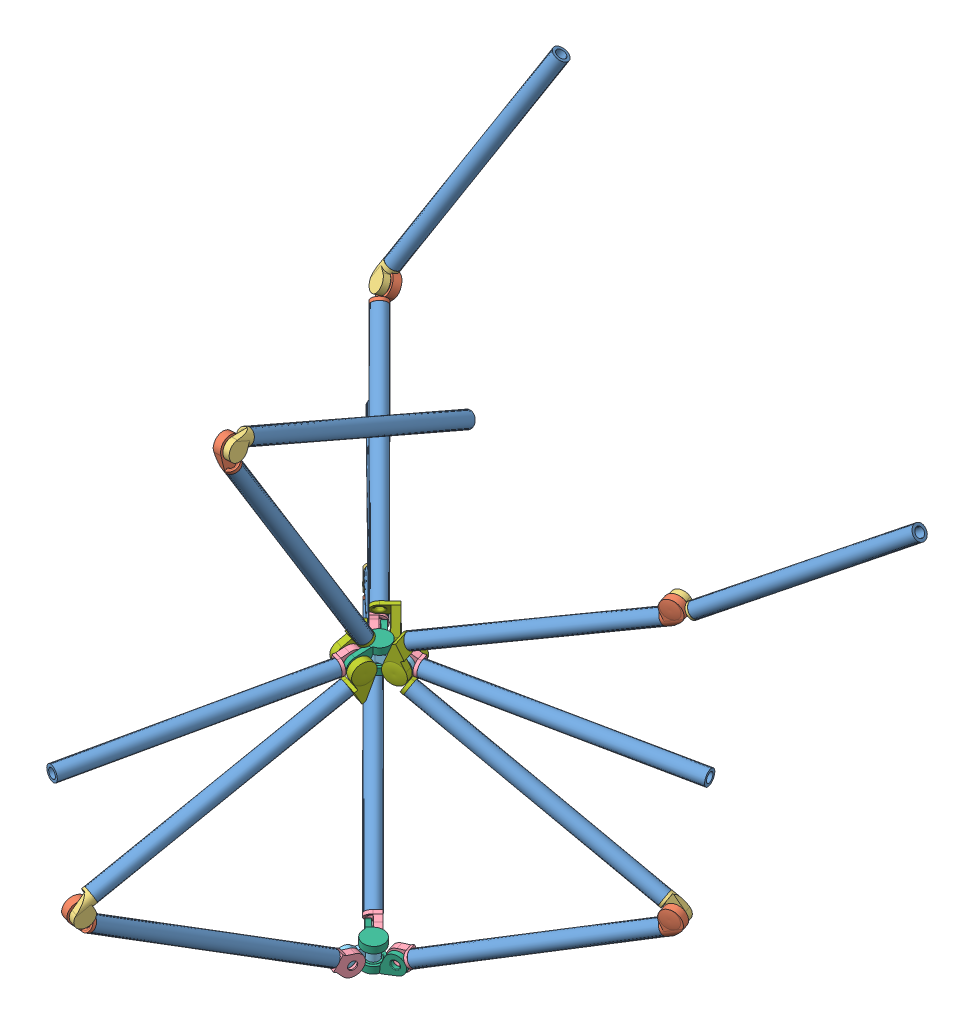
SolidWorks assembly t1d1_part, configuration 默认. Lengths in mm.
Overall size (278.08 283.02 220.4).
56 component instances, 7 part files, 118 mates.
Components (placement in the parent):
- bar-1: bar [默认] at (113.5936 52.6353 -61.7131) x (-0.371564 0.867268 0.331341) z (0.328288 -0.211101 0.920686) size (6.3 100 6.3)
- bar-2: bar [默认] at (-8.2825 55.0819 62.6865) x (0.670703 0.700633 -0.243457) z (-0.719702 0.535343 -0.442082) size (6.3 100 6.3)
- bar-3: bar [默认] at (-59.7571 133.9283 -111.4996) x (-0.460825 0.690997 0.556923) z (0.533513 0.717169 -0.448366) size (6.3 100 6.3)
- bar-4: bar [默认] at (-6.9526 119.8351 80.0325) x (-0.815608 0.545725 -0.192271) z (-0.521971 -0.837348 -0.162465) size (6.3 100 6.3)
- bar-5: bar [默认] at (-46.8523 183.5065 -99.8858) x (-0.20381 0.64879 0.733166) z (0.764001 0.573683 -0.29528) size (6.3 100 6.3)
- bar-6: bar [默认] at (15.7067 217.8918 25.4283) x (0.705225 0.392487 -0.590433) z (-0.706999 0.327058 -0.627044) size (6.3 100 6.3)
- bar-7: bar [默认] at (120.6827 174.6503 -54.6895) x (0.342954 -0.260417 0.902533) z (0.330016 -0.866153 -0.375323) size (6.3 100 6.3)
- bar-8: bar [默认] at (132.1822 116.8072 -62.1166) x (-0.146879 -0.935632 -0.320965) z (-0.23324 0.348095 -0.907981) size (6.3 100 6.3)
- bar-9: bar [默认] at (-53.4278 78.5429 -104.0803) x (-0.389663 -0.567593 0.725259) z (-0.635408 0.735738 0.234405) size (6.3 100 6.3)
- bar-10: bar [默认] at (-7.3739 66.2514 62.9663) x (0.309994 0.781908 0.540855) z (-0.915418 0.399093 -0.052287) size (6.3 100 6.3)
- bar-11: bar [默认] at (114.1097 63.8126 -61.033) x (0.223107 0.716499 -0.660948) z (0.520023 0.486015 0.7024) size (6.3 100 6.3)
- bar-12: bar [默认] at (-54.4851 67.4131 -104.8993) x (-0.705787 0.003815 0.708414) z (0.411489 0.816206 0.405567) size (6.3 100 6.3)
- class2_joint-1: class2_joint [默认] at (100.9145 46.0526 -58.7015) x (0.418964 -0.889781 -0.180995) z (0.265145 -0.070759 0.961609) size (27.33 28 6.67) (flexible)
  - joint_bearing-1: joint_bearing [默认] at origin size (10.85 25 6.67)
  - joint_shaft-1: joint_shaft [默认] at (-22.0945 11.9921 0) x (-0.544886 0.83851 0) z (0 0 -1) size (10.35 24.5 6.35)
- class2_joint-2: class2_joint [默认] at (-5.6632 48.1948 50.0823) x (-0.189599 -0.877668 0.440171) z (-0.965332 0.084713 -0.246895) size (27.33 28 6.67) (flexible)
  - joint_bearing-1: joint_bearing [默认] at origin size (10.85 25 6.67)
  - joint_shaft-1: joint_shaft [默认] at (-22.0945 11.9921 0) x (-0.544886 0.83851 0) z (0 0 -1) size (10.35 24.5 6.35)
- class2_joint-3: class2_joint [默认] at (107.8424 168.4224 -51.6073) x (0.395255 -0.901683 -0.175333) z (0.265145 -0.070759 0.961609) size (27.33 28 6.67) (flexible)
  - joint_bearing-1: joint_bearing [默认] at origin size (10.85 25 6.67)
  - joint_shaft-1: joint_shaft [默认] at (-4.0164 41.2273 0) x (0.981197 0.193011 0) z (0 0 -1) size (10.35 24.5 6.35)
- class2_joint-4: class2_joint [默认] at (16.4805 205.341 18.0095) x (0.032784 -0.507081 0.861275) z (-0.998056 -0.062307 0.001307) size (27.33 28 6.67) (flexible)
  - joint_bearing-1: joint_bearing [默认] at origin size (10.85 25 6.67)
  - joint_shaft-1: joint_shaft [默认] at (-17.9686 5.9577 0) x (-0.801912 0.597442 0) z (0 0 -1) size (10.35 24.5 6.35)
- class2_joint-9: class2_joint [默认] at (-46.0658 58.978 -96.4658) x (-0.420307 -0.816094 -0.396652) z (0.700571 -0.01405 -0.713444) size (27.33 28 6.67) (flexible)
  - joint_bearing-1: joint_bearing [默认] at origin size (10.85 25 6.67)
  - joint_shaft-1: joint_shaft [默认] at (-22.0945 11.9921 0) x (-0.544886 0.83851 0) z (0 0 -1) size (10.35 24.5 6.35)
- joint_bearing_central-1: joint_bearing_central [默认] at (7.0386 14.7969 -11.0395) x (-0.191063 -0.877539 0.439796) z (0.965044 -0.086044 0.247563) size (9 25 6.17)
- mid_ear-1: mid_ear [默认] at (12.7874 2.9254 -37.5756) x (0.965044 -0.086044 0.247563) z (-0.251035 -0.032026 0.967448) size (5 8 15.5)
- side_ear-1: side_ear [默认] at (13.164 7.9042 -37.313) x (0.699933 -0.015288 -0.714045) z (-0.710226 0.090529 -0.698128) size (9 9.5 17.5)
- side_ear-2: side_ear [默认] at (12.7874 2.9254 -37.5756) x (-0.265145 0.070759 -0.961609) z (0.961262 -0.058502 -0.269355) size (9 9.5 17.5)
- joint_bearing_central-2: joint_bearing_central [默认] at (-5.238 18.0734 -55.569) x (0.421369 0.816072 0.395569) z (0.699933 -0.015288 -0.714045) size (9 25 6.17)
- joint_bearing_central-3: joint_bearing_central [默认] at (39.4298 14.1311 -44.0971) x (0.418964 -0.889781 -0.180995) z (-0.265145 0.070759 -0.961609) size (9 25 6.17)
- joint_bearing_central-4: joint_bearing_central [默认] at (50.0904 121.8032 -39.1137) x (-0.075315 -0.995776 -0.052506) z (-0.265145 0.070759 -0.961609) size (9 25 6.17)
- mid_ear-2: mid_ear [默认] at (21.5449 121.0396 -31.299) x (-0.265145 0.070759 -0.961609) z (0.961262 -0.058502 -0.269355) size (5 8 15.5)
- side_ear-3: side_ear [默认] at (21.9214 126.0184 -31.0364) x (-0.965401 0.085998 -0.246183) z (-0.249659 -0.032148 0.9678) size (9 9.5 17.5)
- side_ear-4: side_ear [默认] at (21.5449 121.0396 -31.299) x (-0.700945 0.015417 0.713048) z (-0.709227 0.090507 -0.699146) size (9 9.5 17.5)
- joint_bearing_central-5: joint_bearing_central [默认] at (14.3682 122.5806 -2.6176) x (0.075315 0.995776 0.052506) z (-0.965401 0.085998 -0.246183) size (9 25 6.17)
- joint_bearing_central-6: joint_bearing_central [默认] at (0.8109 126.199 -51.7925) x (-0.075315 -0.995776 -0.052506) z (-0.700945 0.015417 0.713048) size (9 25 6.17)
- joint_bearing_c9-1: joint_bearing_c9 [默认] at (5.4279 140.81 -47.5699) x (0.36594 0.865912 0.341006) z (0.700945 -0.015417 -0.713048) size (14.86 25 10.02)
- joint_bearing_c9-2: joint_bearing_c9 [默认] at (20.233 144.4782 -17.9667) x (0.255329 0.503604 -0.825342) z (-0.965401 0.085998 -0.246183) size (14.86 25 10.02)
- joint_bearing_c9-3: joint_bearing_c9 [默认] at (43.6975 106.5484 -38.4735) x (-0.499899 -0.862887 0.074343) z (-0.265145 0.070759 -0.961609) size (14.86 25 10.02)
- joint_bearing_c9-4: joint_bearing_c9 [默认] at (45.5758 138.2212 -36.6608) x (-0.395255 0.901683 0.175333) z (0.265145 -0.070759 0.961609) size (14.86 25 10.02)
- joint_bearing_c9-5: joint_bearing_c9 [默认] at (14.5513 107.1494 -8.726) x (0.045702 -0.873647 -0.484409) z (0.965401 -0.085998 0.246183) size (14.86 25 10.02)
- joint_bearing_c9-6: joint_bearing_c9 [默认] at (3.5039 110.0979 -48.7972) x (0.253489 -0.929104 0.269275) z (-0.700945 0.015417 0.713048) size (14.86 25 10.02)
- class2_joint-10: class2_joint [默认] at (-37.9145 176.2071 -90.9418) x (-0.678772 -0.729666 0.082807) z (0.405592 -0.466507 -0.786045) size (27.33 28 6.67) (flexible)
  - joint_bearing-1: joint_bearing [默认] at origin size (10.85 25 6.67)
  - joint_shaft-1: joint_shaft [默认] at (-21.476 30.2674 0) x (0.330272 0.943886 0) z (0 0 -1) size (10.35 24.5 6.35)
- bar-13: bar [默认] at (-4.4185 279.9281 -135.2153) x (-0.501301 -0.026657 -0.864862) z (-0.745934 0.519847 0.416343) size (6.3 100 6.3)
- bar-14: bar [默认] at (209.6928 240.2368 -74.4062) x (0.27836 -0.089864 0.956264) z (0.551093 -0.800481 -0.235642) size (6.3 100 6.3)
- bar-15: bar [默认] at (17.5327 186.5748 -73.1816) x (-0.999563 0.00835 -0.028341) z (0.01865 0.92229 -0.386047) size (6.3 100 6.3)
- mid_ear-3: mid_ear [默认] at (21.5449 121.0396 -31.299) x (-0.265145 0.070759 -0.961609) z (0.961262 -0.058502 -0.269355) size (5 8 15.5)
- joint_bearing_central-7: joint_bearing_central [默认] at (50.0904 121.8032 -39.1137) x (-0.075315 -0.995776 -0.052506) z (-0.265145 0.070759 -0.961609) size (9 25 6.17)
- side_ear-5: side_ear [默认] at (12.7874 2.9254 -37.5756) x (-0.265145 0.070759 -0.961609) z (0.961262 -0.058502 -0.269355) size (9 9.5 17.5)
- side_ear-6: side_ear [默认] at (13.164 7.9042 -37.313) x (0.699933 -0.015288 -0.714045) z (-0.710226 0.090529 -0.698128) size (9 9.5 17.5)
- mid_ear-4: mid_ear [默认] at (12.7874 2.9254 -37.5756) x (0.965044 -0.086044 0.247563) z (-0.251035 -0.032026 0.967448) size (5 8 15.5)
Mates (geometry in assembly coordinates):
- 同心4: concentric anti-aligned: cylinder of bar-1 through (26.7508 7.5484 -41.0855) axis (0.868428 0.450869 -0.206276) radius 2; cylinder of class2_joint-1/joint_bearing-1 through (114.8094 53.2665 -62.0019) axis (-0.868428 -0.450869 0.206276) radius 2
- 重合4: coincident anti-aligned: plane of bar-1 through (113.5936 52.6353 -61.7131) normal (0.868428 0.450869 -0.206276); plane of class2_joint-1/joint_bearing-1 through (113.5936 52.6353 -61.7131) normal (-0.868428 -0.450869 0.206276)
- 同心5: concentric anti-aligned: cylinder of bar-11 through (31.6598 113.8545 -34.6167) axis (0.824499 -0.500419 -0.264163) radius 2; cylinder of class2_joint-1/joint_shaft-1 through (115.264 63.112 -61.4028) axis (-0.824499 0.500419 0.264163) radius 2
- 重合6: coincident anti-aligned: plane of bar-11 through (114.1097 63.8126 -61.033) normal (0.824499 -0.500419 -0.264163); plane of class2_joint-1/joint_shaft-1 through (114.1097 63.8126 -61.033) normal (-0.824499 0.500419 0.264163)
- 同心6: concentric anti-aligned: cylinder of bar-2 through (9.6579 7.9097 -23.6438) axis (-0.179404 0.471722 0.863303) radius 2; cylinder of class2_joint-2/joint_bearing-1 through (-8.5337 55.7423 63.8952) axis (0.179404 -0.471722 -0.863303) radius 2
- 重合7: coincident anti-aligned: plane of bar-2 through (-8.2825 55.0819 62.6865) normal (-0.179404 0.471722 0.863303); plane of class2_joint-2/joint_bearing-1 through (-8.2825 55.0819 62.6865) normal (0.179404 -0.471722 -0.863303)
- 同心7: concentric anti-aligned: cylinder of bar-10 through (18.2996 114.1414 -20.9826) axis (-0.256736 -0.478899 0.839489) radius 2; cylinder of class2_joint-2/joint_shaft-1 through (-7.7334 65.581 64.1416) axis (0.256736 0.478899 -0.839489) radius 2
- 重合9: coincident anti-aligned: plane of bar-10 through (-7.3739 66.2514 62.9663) normal (-0.256736 -0.478899 0.839489); plane of class2_joint-2/joint_shaft-1 through (-7.3739 66.2514 62.9663) normal (0.256736 0.478899 -0.839489)
- 同心8: concentric anti-aligned: cylinder of bar-12 through (3.1813 9.6383 -47.1355) axis (-0.576664 0.577748 -0.577638) radius 2; cylinder of class2_joint-9/joint_bearing-1 through (-55.2925 68.2219 -105.708) axis (0.576664 -0.577748 0.577638) radius 2
- 重合10: coincident anti-aligned: plane of bar-12 through (-54.4851 67.4131 -104.8993) normal (-0.576664 0.577748 -0.577638); plane of class2_joint-9/joint_bearing-1 through (-54.4851 67.4131 -104.8993) normal (0.576664 -0.577748 0.577638)
- 同心9: concentric anti-aligned: cylinder of bar-9 through (13.2369 115.4926 -39.346) axis (-0.666648 -0.369497 -0.647343) radius 2; cylinder of class2_joint-9/joint_shaft-1 through (-54.3612 78.0256 -104.9865) axis (0.666648 0.369497 0.647343) radius 2
- 重合12: coincident anti-aligned: plane of bar-9 through (-53.4278 78.5429 -104.0803) normal (-0.666648 -0.369497 -0.647343); plane of class2_joint-9/joint_shaft-1 through (-53.4278 78.5429 -104.0803) normal (0.666648 0.369497 0.647343)
- 同心25: concentric anti-aligned: cylinder of bar-7 through (32.7355 131.9933 -33.5786) axis (0.879472 0.426569 -0.211109) radius 2; cylinder of class2_joint-3/joint_bearing-1 through (121.914 175.2475 -54.985) axis (-0.879472 -0.426569 0.211109) radius 2
- 重合27: coincident anti-aligned: plane of bar-7 through (120.6827 174.6503 -54.6895) normal (0.879472 0.426569 -0.211109); plane of class2_joint-3/joint_bearing-1 through (120.6827 174.6503 -54.6895) normal (-0.879472 -0.426569 0.211109)
- 同心26: concentric anti-aligned: cylinder of bar-6 through (21.0068 131.9274 -25.3855) axis (-0.053001 0.859644 0.508138) radius 2; cylinder of class2_joint-4/joint_bearing-1 through (15.6325 219.0953 26.1397) axis (0.053001 -0.859644 -0.508138) radius 2
- 重合32: coincident anti-aligned: plane of bar-6 through (15.7067 217.8918 25.4283) normal (-0.053001 0.859644 0.508138); plane of class2_joint-4/joint_bearing-1 through (15.7067 217.8918 25.4283) normal (0.053001 -0.859644 -0.508138)
- 同心27: concentric anti-aligned: cylinder of bar-5 through (14.3657 133.5106 -38.6259) axis (-0.61218 0.499959 -0.612598) radius 2; cylinder of class2_joint-10/joint_bearing-1 through (-47.7093 184.2064 -100.7434) axis (0.61218 -0.499959 0.612598) radius 2
- 重合35: coincident anti-aligned: plane of bar-5 through (-46.8523 183.5065 -99.8858) normal (-0.61218 0.499959 -0.612598); plane of class2_joint-10/joint_bearing-1 through (-46.8523 183.5065 -99.8858) normal (0.61218 -0.499959 0.612598)
- 同心28: concentric aligned: cylinder of class2_joint-10/joint_shaft-1 through (-48.8822 193.3484 -106.7742) axis (0.438497 0.853843 -0.280484) radius 2; cylinder of bar-13 through (-48.2683 194.5438 -107.1669) axis (0.438497 0.853843 -0.280484) radius 2
- 重合37: coincident anti-aligned: plane of class2_joint-10/joint_shaft-1 through (-48.2683 194.5438 -107.1669) normal (0.438497 0.853843 -0.280484); plane of bar-13 through (-48.2683 194.5438 -107.1669) normal (-0.438497 -0.853843 0.280484)
- 同心29: concentric aligned: cylinder of class2_joint-3/joint_shaft-1 through (129.9268 180.1489 -56.8338) axis (0.786646 0.592583 -0.173298) radius 2; cylinder of bar-14 through (131.0281 180.9785 -57.0764) axis (0.786646 0.592583 -0.173298) radius 2
- 重合38: coincident anti-aligned: plane of class2_joint-3/joint_shaft-1 through (131.0281 180.9785 -57.0764) normal (0.786646 0.592583 -0.173298); plane of bar-14 through (131.0281 180.9785 -57.0764) normal (-0.786646 -0.592583 0.173298)
- 同心32: concentric aligned: cylinder of class2_joint-4/joint_shaft-1 through (15.209 225.7566 20.3136) axis (0.022915 -0.386407 -0.922044) radius 2; cylinder of bar-15 through (15.2411 225.2156 19.0227) axis (0.022915 -0.386407 -0.922044) radius 2
- 重合39: coincident anti-aligned: plane of class2_joint-4/joint_shaft-1 through (15.2411 225.2156 19.0227) normal (0.022915 -0.386407 -0.922044); plane of bar-15 through (15.2411 225.2156 19.0227) normal (-0.022915 0.386407 0.922044)
- 同心34: concentric anti-aligned: cylinder of bar-2 through (9.6579 7.9097 -23.6438) axis (-0.179404 0.471722 0.863303) radius 2; cylinder of class2_joint-2/joint_bearing-1 through (-8.5337 55.7423 63.8952) axis (0.179404 -0.471722 -0.863303) radius 2
- 同心36: concentric anti-aligned: cylinder of bar-1 through (26.7508 7.5484 -41.0855) axis (0.868428 0.450869 -0.206276) radius 3.15; cylinder of class2_joint-1/joint_bearing-1 through (114.8094 53.2665 -62.0019) axis (-0.868428 -0.450869 0.206276) radius 2
- 重合44: coincident anti-aligned: plane of bar-1 through (113.5936 52.6353 -61.7131) normal (0.868428 0.450869 -0.206276); plane of class2_joint-1/joint_bearing-1 through (113.5936 52.6353 -61.7131) normal (-0.868428 -0.450869 0.206276)
- 同心3: concentric anti-aligned: cylinder of joint_bearing_central-1 through (13.129 4.9115 -28.1184) axis (-0.965044 0.086044 -0.247563) radius 3.15; cylinder of mid_ear-1 through (8.3028 5.3418 -29.3564) axis (0.965044 -0.086044 0.247563) radius 1.65
- 距离4: distance = 0.5 mm anti-aligned: plane of joint_bearing_central-1 through (10.7164 5.1266 -28.7373) normal (-0.965044 0.086044 -0.247563); plane of mid_ear-1 through (13.2719 7.5295 -39.8836) normal (0.965044 -0.086044 0.247563)
- 角度8: planar angle = 2.094395 rad: plane of joint_bearing_central-1 through (0.6375 10.4133 -26.1812) normal (-0.221682 0.235914 0.946151); plane of side_ear-1 through (13.3899 10.8916 -37.1555) normal (0.075315 0.995776 0.052506)
- 同心1: concentric aligned: cylinder of mid_ear-1 through (13.164 7.9042 -37.313) axis (-0.075315 -0.995776 -0.052506) radius 1.65; cylinder of side_ear-1 through (13.3146 9.8958 -37.208) axis (-0.075315 -0.995776 -0.052506) radius 3.15
- 重合2: coincident anti-aligned: plane of mid_ear-1 through (13.164 7.9042 -37.313) normal (0.075315 0.995776 0.052506); plane of side_ear-1 through (13.164 7.9042 -37.313) normal (-0.075315 -0.995776 -0.052506)
- 同心2: concentric anti-aligned: cylinder of mid_ear-1 through (13.164 7.9042 -37.313) axis (-0.075315 -0.995776 -0.052506) radius 1.65; cylinder of side_ear-2 through (12.6368 0.9338 -37.6806) axis (0.075315 0.995776 0.052506) radius 3.15
- 重合3: coincident anti-aligned: plane of mid_ear-1 through (12.7874 2.9254 -37.5756) normal (-0.075315 -0.995776 -0.052506); plane of side_ear-2 through (12.7874 2.9254 -37.5756) normal (0.075315 0.995776 0.052506)
- 角度4: planar angle = 2.094395 rad: plane of side_ear-2 through (5.3043 6.2724 -42.704) normal (0.325091 0.025259 -0.945345); plane of mid_ear-1 through (11.3418 7.7016 -40.3787) normal (-0.965044 0.086044 -0.247563)
- 角度5: planar angle = 2.094395 rad: plane of mid_ear-1 through (11.3418 7.7016 -40.3787) normal (-0.965044 0.086044 -0.247563); plane of joint_bearing_central-2
- 同心42: concentric anti-aligned: cylinder of side_ear-1 through (4.8338 6.2678 -41.9423) axis (0.699933 -0.015288 -0.714045) radius 1.65; cylinder of joint_bearing_central-2 through (8.3335 6.1913 -45.5126) axis (-0.699933 0.015288 0.714045) radius 3.15
- 同心43: concentric anti-aligned: cylinder of side_ear-1 through (4.8338 6.2678 -41.9423) axis (0.699933 -0.015288 -0.714045) radius 1.65; cylinder of joint_bearing_central-2 through (8.3335 6.1913 -45.5126) axis (-0.699933 0.015288 0.714045) radius 3.15
- 距离2: distance = 0.5 mm anti-aligned: plane of side_ear-1 through (12.814 7.9119 -36.956) normal (0.699933 -0.015288 -0.714045); plane of joint_bearing_central-2 through (6.5836 6.2296 -43.7275) normal (-0.699933 0.015288 0.714045)
- 角度6: planar angle = 1.047198 rad: plane of side_ear-1 through (13.3899 10.8916 -37.1555) normal (0.075315 0.995776 0.052506); plane of joint_bearing_central-3 through (6.3421 13.0272 -49.6228) normal (-0.604042 0.774697 -0.187022)
- 角度7: planar angle = 2.094395 rad: plane of joint_bearing_central-2 through (17.6179 2.6651 -19.9624) normal (-0.251263 0.239739 0.937759); plane of side_ear-1 through (13.3899 10.8916 -37.1555) normal (0.075315 0.995776 0.052506)
- 同心44: concentric anti-aligned: cylinder of side_ear-2 through (22.2899 4.7114 -37.4645) axis (-0.265145 0.070759 -0.961609) radius 1.65; cylinder of joint_bearing_central-3 through (20.9642 5.0652 -42.2725) axis (0.265145 -0.070759 0.961609) radius 3.15
- 距离3: distance = 0.5 mm anti-aligned: plane of side_ear-2 through (12.92 2.89 -37.0948) normal (-0.265145 0.070759 -0.961609); plane of joint_bearing_central-3 through (21.627 4.8883 -39.8685) normal (0.265145 -0.070759 0.961609)
- 同心45: concentric aligned: cylinder of bar-2 through (9.6579 7.9097 -23.6438) axis (-0.179404 0.471722 0.863303) radius 2; cylinder of joint_bearing_central-1 through (9.909 7.2493 -24.8524) axis (-0.179404 0.471722 0.863303) radius 2
- 重合47: coincident anti-aligned: plane of bar-2 through (9.6579 7.9097 -23.6438) normal (0.179404 -0.471722 -0.863303); plane of joint_bearing_central-1 through (1.0496 11.5175 -27.404) normal (-0.179404 0.471722 0.863303)
- 平行27: parallel: plane of class2_joint-2/joint_bearing-1; plane of joint_bearing_central-1 through (10.7164 5.1266 -28.7373) normal (-0.965044 0.086044 -0.247563)
- 平行30: parallel: plane of assembly through (0 0 0) normal (0 1 0); plane of side_ear-1 through (13.3899 10.8916 -37.1555) normal (0.075315 0.995776 0.052506); plane of assembly
- 同心46: concentric aligned: cylinder of bar-12 through (3.1813 9.6383 -47.1355) axis (-0.576664 0.577748 -0.577638) radius 2; cylinder of joint_bearing_central-2 through (3.9886 8.8294 -46.3268) axis (-0.576664 0.577748 -0.577638) radius 2
- 重合48: coincident anti-aligned: plane of bar-12 through (3.1813 9.6383 -47.1355) normal (0.576664 -0.577748 0.577638); plane of joint_bearing_central-2 through (-4.84 7.1932 -41.5733) normal (-0.576664 0.577748 -0.577638)
- 平行32: parallel: plane of class2_joint-9/joint_bearing-1; plane of joint_bearing_central-2
- 同心47: concentric aligned: cylinder of bar-1 through (26.7508 7.5484 -41.0855) axis (0.868428 0.450869 -0.206276) radius 2; cylinder of joint_bearing_central-3 through (25.535 6.9172 -40.7967) axis (0.868428 0.450869 -0.206276) radius 2
- 重合49: coincident anti-aligned: plane of bar-1 through (26.7508 7.5484 -41.0855) normal (-0.868428 -0.450869 0.206276); plane of joint_bearing_central-3 through (27.9523 9.6978 -31.3288) normal (0.868428 0.450869 -0.206276)
- 平行33: parallel anti-aligned: plane of class2_joint-1/joint_bearing-1 through (117.3871 58.1205 -62.3555) normal (-0.265145 0.070759 -0.961609); plane of joint_bearing_central-3 through (21.627 4.8883 -39.8685) normal (0.265145 -0.070759 0.961609)
- 同心48: concentric anti-aligned: cylinder of joint_bearing_central-4 through (29.7216 123.1794 -35.9959) axis (0.265145 -0.070759 0.961609) radius 3.15; cylinder of mid_ear-2 through (31.0476 122.8255 -31.1869) axis (-0.265145 0.070759 -0.961609) radius 1.65
- 距离5: distance = 0.5 mm anti-aligned: plane of joint_bearing_central-4 through (30.3845 123.0025 -33.5919) normal (0.265145 -0.070759 0.961609); plane of mid_ear-2 through (19.6113 125.6315 -29.908) normal (-0.265145 0.070759 -0.961609)
- 同心12: concentric aligned: cylinder of joint_bearing_central-4 through (29.5424 123.2272 -36.646) axis (0.265145 -0.070759 0.961609) radius 1.8; cylinder of joint_bearing_c9-3 through (28.7207 123.4465 -39.626) axis (0.265145 -0.070759 0.961609) radius 3.15
- 距离11: distance = 0.5 mm anti-aligned: plane of joint_bearing_c9-3 through (29.4565 123.2501 -36.9575) normal (0.265145 -0.070759 0.961609); plane of joint_bearing_central-4 through (29.5891 123.2148 -36.4767) normal (-0.265145 0.070759 -0.961609)
- 角度1: planar angle = 2.094395 rad: plane of joint_bearing_central-4 through (11.0012 73.6035 -33.1279) normal (-0.325091 -0.025259 0.945345); plane of joint_bearing_central-5 through (15.1528 72.8717 -25.2045) normal (-0.959979 0.086651 -0.26633)
- 平行5: parallel: plane of joint_bearing_central-4; plane of side_ear-3 through (22.3132 128.8711 -30.9346) normal (0.075315 0.995776 0.052506)
- 同心49: concentric aligned: cylinder of mid_ear-2 through (21.9214 126.0184 -31.0364) axis (-0.075315 -0.995776 -0.052506) radius 1.65; cylinder of side_ear-3 through (22.0721 128.01 -30.9314) axis (-0.075315 -0.995776 -0.052506) radius 3.15
- 重合50: coincident anti-aligned: plane of mid_ear-2 through (21.9214 126.0184 -31.0364) normal (0.075315 0.995776 0.052506); plane of side_ear-3 through (21.9214 126.0184 -31.0364) normal (-0.075315 -0.995776 -0.052506)
- 同心50: concentric anti-aligned: cylinder of mid_ear-2 through (21.9214 126.0184 -31.0364) axis (-0.075315 -0.995776 -0.052506) radius 1.65; cylinder of side_ear-4 through (21.3942 119.048 -31.404) axis (0.075315 0.995776 0.052506) radius 3.15
- 重合51: coincident anti-aligned: plane of mid_ear-2 through (21.5449 121.0396 -31.299) normal (-0.075315 -0.995776 -0.052506); plane of side_ear-4 through (21.5449 121.0396 -31.299) normal (0.075315 0.995776 0.052506)
- 同心11: concentric aligned: cylinder of mid_ear-2 through (31.0476 122.8255 -31.1869) axis (-0.265145 0.070759 -0.961609) radius 1.65; cylinder of joint_bearing_c9-4 through (32.0483 122.5585 -27.5578) axis (-0.265145 0.070759 -0.961609) radius 3.15
- 距离10: distance = 1 mm anti-aligned: plane of mid_ear-2 through (20.1416 125.49 -27.9848) normal (0.265145 -0.070759 0.961609); plane of joint_bearing_c9-4 through (31.3125 122.7548 -30.2263) normal (-0.265145 0.070759 -0.961609)
- 角度2: planar angle = 2.094395 rad: plane of joint_bearing_central-6; plane of mid_ear-2
- 同心51: concentric anti-aligned: cylinder of side_ear-3 through (21.8997 123.0247 -21.8421) axis (-0.965401 0.085998 -0.246183) radius 1.65; cylinder of joint_bearing_central-5 through (17.0727 123.4547 -23.073) axis (0.965401 -0.085998 0.246183) radius 3.15
- 同心52: concentric anti-aligned: cylinder of side_ear-3 through (21.8997 123.0247 -21.8421) axis (-0.965401 0.085998 -0.246183) radius 1.65; cylinder of joint_bearing_central-5 through (17.0727 123.4547 -23.073) axis (0.965401 -0.085998 0.246183) radius 3.15
- 距离12: distance = 0.5 mm anti-aligned: plane of side_ear-3 through (22.4041 125.9754 -30.9134) normal (-0.965401 0.085998 -0.246183); plane of joint_bearing_central-5 through (19.4862 123.2397 -22.4575) normal (0.965401 -0.085998 0.246183)
- 同心53: concentric aligned: cylinder of side_ear-3 through (21.8997 123.0247 -21.8421) axis (-0.965401 0.085998 -0.246183) radius 1.65; cylinder of joint_bearing_c9-5 through (25.5441 122.7 -20.9127) axis (-0.965401 0.085998 -0.246183) radius 3.15
- 距离7: distance = 1 mm anti-aligned: plane of side_ear-3 through (21.8997 123.0247 -21.8421) normal (0.965401 -0.085998 0.246183); plane of joint_bearing_c9-5 through (22.8651 122.9387 -21.5959) normal (-0.965401 0.085998 -0.246183)
- 平行3: parallel: plane of side_ear-3 through (22.3132 128.8711 -30.9346) normal (0.075315 0.995776 0.052506); plane of joint_bearing_central-6 through (19.2333 127.6321 -47.2995) normal (0.075315 0.995776 0.052506)
- 平行4: parallel: plane of side_ear-3 through (22.3132 128.8711 -30.9346) normal (0.075315 0.995776 0.052506); plane of joint_bearing_central-5 through (27.6126 125.2571 -14.2778) normal (0.075315 0.995776 0.052506)
- 相切1: tangent: cylinder of side_ear-3 through (22.3132 128.8711 -30.9346) axis (-0.075315 -0.995776 -0.052506) radius 4.5; plane of joint_bearing_c9-4
- 相切2: tangent: cylinder of side_ear-3 through (22.3132 128.8711 -30.9346) axis (-0.075315 -0.995776 -0.052506) radius 4.5; plane of joint_bearing_c9-1
- 相切3: tangent: cylinder of side_ear-3 through (22.3132 128.8711 -30.9346) axis (-0.075315 -0.995776 -0.052506) radius 4.5; plane of joint_bearing_c9-2
- 同心54: concentric anti-aligned: cylinder of side_ear-4 through (17.1025 124.305 -39.2426) axis (-0.700945 0.015417 0.713048) radius 1.65; cylinder of joint_bearing_central-6 through (13.5977 124.3821 -35.6774) axis (0.700945 -0.015417 -0.713048) radius 3.15
- 距离13: distance = 0.5 mm anti-aligned: plane of side_ear-4 through (21.8953 121.0319 -31.6555) normal (-0.700945 0.015417 0.713048); plane of joint_bearing_central-6 through (15.3501 124.3436 -37.46) normal (0.700945 -0.015417 -0.713048)
- 同心55: concentric aligned: cylinder of side_ear-4 through (17.1025 124.305 -39.2426) axis (-0.700945 0.015417 0.713048) radius 1.65; cylinder of joint_bearing_c9-1 through (19.7485 124.2468 -41.9344) axis (-0.700945 0.015417 0.713048) radius 3.15
- 距离14: distance = 1 mm anti-aligned: plane of side_ear-4 through (17.1025 124.305 -39.2426) normal (0.700945 -0.015417 -0.713048); plane of joint_bearing_c9-1 through (17.8034 124.2896 -39.9557) normal (-0.700945 0.015417 0.713048)
- 相切7: tangent: cylinder of side_ear-4 through (21.4848 117.9176 -31.5121) axis (0.075315 0.995776 0.052506) radius 4.5; plane of joint_bearing_c9-6 through (10.5716 113.0253 -33.0017) normal (0.640668 -0.428445 0.637164)
- 相切8: tangent: cylinder of side_ear-4 through (21.4848 117.9176 -31.5121) axis (0.075315 0.995776 0.052506) radius 4.5; plane of joint_bearing_c9-3 through (27.4149 112.1343 -40.3321) normal (-0.926701 -0.294179 0.233847)
- 相切9: tangent: cylinder of side_ear-4 through (21.3189 118.0522 -31.4565) axis (0.075315 0.995776 0.052506) radius 4.5; plane of joint_bearing_c9-5 through (25.0793 111.479 -22.0957) normal (0.208581 -0.311955 -0.926919)
- 同心10: concentric aligned: cylinder of joint_bearing_central-5 through (16.4201 123.5128 -23.2394) axis (0.965401 -0.085998 0.246183) radius 1.8; cylinder of joint_bearing_c9-2 through (13.4283 123.7793 -24.0023) axis (0.965401 -0.085998 0.246183) radius 3.15
- 距离9: distance = 0.5 mm anti-aligned: plane of joint_bearing_c9-2 through (16.1073 123.5407 -23.3192) normal (0.965401 -0.085998 0.246183); plane of joint_bearing_central-5 through (16.59 123.4977 -23.1961) normal (-0.965401 0.085998 -0.246183)
- 同心56: concentric aligned: cylinder of joint_bearing_central-6 through (13.1239 124.3925 -35.1954) axis (0.700945 -0.015417 -0.713048) radius 1.8; cylinder of joint_bearing_c9-6 through (10.9517 124.4403 -32.9856) axis (0.700945 -0.015417 -0.713048) radius 3.15
- 距离6: distance = 0.5 mm anti-aligned: plane of joint_bearing_c9-6 through (12.8968 124.3975 -34.9644) normal (0.700945 -0.015417 -0.713048); plane of joint_bearing_central-6 through (13.2473 124.3898 -35.3209) normal (-0.700945 0.015417 0.713048)
- 同心57: concentric aligned: cylinder of bar-8 through (36.056 122.6573 -35.1811) axis (0.961262 -0.058502 -0.269355) radius 2; cylinder of joint_bearing_central-4 through (34.7102 122.7392 -34.804) axis (0.961262 -0.058502 -0.269355) radius 2
- 重合52: coincident anti-aligned: plane of bar-8 through (36.056 122.6573 -35.1811) normal (-0.961262 0.058502 0.269355); plane of joint_bearing_central-4 through (38.8269 125.1433 -25.8323) normal (0.961262 -0.058502 -0.269355)
- 平行34: parallel: plane of class2_joint-4/joint_bearing-1 through (15.2899 224.5737 25.6918) normal (0.998056 0.062307 -0.001307); plane of side_ear-3 through (22.4041 125.9754 -30.9134) normal (-0.965401 0.085998 -0.246183)
- 平行35: parallel: plane of mid_ear-1 through (11.3418 7.7016 -40.3787) normal (-0.965044 0.086044 -0.247563); plane of side_ear-3 through (21.8997 123.0247 -21.8421) normal (0.965401 -0.085998 0.246183)
- 平行36: parallel: plane of side_ear-1 through (13.3899 10.8916 -37.1555) normal (0.075315 0.995776 0.052506); plane of side_ear-3 through (22.1474 129.0058 -30.8789) normal (0.075315 0.995776 0.052506)
- 平行37: parallel anti-aligned: plane of side_ear-4 through (21.3189 118.0522 -31.4565) normal (-0.075315 -0.995776 -0.052506); plane of side_ear-1 through (13.3899 10.8916 -37.1555) normal (0.075315 0.995776 0.052506)
- 同心58: concentric aligned: cylinder of bar-4 through (18.0132 123.05 -16.7475) axis (-0.249659 -0.032148 0.9678) radius 2; cylinder of joint_bearing_central-5 through (18.3628 123.095 -18.1024) axis (-0.249659 -0.032148 0.9678) radius 2
- 重合53: coincident anti-aligned: plane of bar-4 through (18.0132 123.05 -16.7475) normal (0.249659 0.032148 -0.9678); plane of joint_bearing_central-5 through (26.9924 119.0672 -14.5635) normal (-0.249659 -0.032148 0.9678)
- 同心59: concentric aligned: cylinder of bar-3 through (11.1657 124.8776 -41.585) axis (-0.709227 0.090507 -0.699146) radius 2; cylinder of joint_bearing_central-6 through (12.1586 124.7508 -40.6062) axis (-0.709227 0.090507 -0.699146) radius 2
- 重合54: coincident anti-aligned: plane of bar-3 through (11.1657 124.8776 -41.585) normal (0.709227 -0.090507 0.699146); plane of joint_bearing_central-6 through (18.0979 127.8919 -48.2269) normal (-0.709227 0.090507 -0.699146)
- 平行38: parallel: plane of joint_bearing_central-6; plane of class2_joint-10/joint_shaft-1
- 同心60: concentric aligned: cylinder of bar-5 through (14.3657 133.5106 -38.6259) axis (-0.61218 0.499959 -0.612598) radius 2; cylinder of joint_bearing_c9-1 through (15.2227 132.8106 -37.7683) axis (-0.61218 0.499959 -0.612598) radius 2
- 重合55: coincident anti-aligned: plane of bar-5 through (14.3657 133.5106 -38.6259) normal (0.61218 -0.499959 0.612598); plane of joint_bearing_c9-1 through (10.9776 130.8103 -37.444) normal (-0.61218 0.499959 -0.612598)
- 同心61: concentric aligned: cylinder of bar-6 through (21.0068 131.9274 -25.3855) axis (-0.053001 0.859644 0.508138) radius 2; cylinder of joint_bearing_c9-2 through (21.081 130.7239 -26.0969) axis (-0.053001 0.859644 0.508138) radius 2
- 重合56: coincident anti-aligned: plane of bar-6 through (21.0068 131.9274 -25.3855) normal (0.053001 -0.859644 -0.508138); plane of joint_bearing_c9-2 through (23.2622 130.0554 -21.9831) normal (-0.053001 0.859644 0.508138)
- 同心62: concentric aligned: cylinder of bar-11 through (31.6598 113.8545 -34.6167) axis (0.824499 -0.500419 -0.264163) radius 2; cylinder of joint_bearing_c9-3 through (30.5055 114.5551 -34.2469) axis (0.824499 -0.500419 -0.264163) radius 2
- 同心63: concentric aligned: cylinder of bar-7 through (32.7355 131.9933 -33.5786) axis (0.879472 0.426569 -0.211109) radius 2; cylinder of joint_bearing_c9-4 through (31.5042 131.3961 -33.283) axis (0.879472 0.426569 -0.211109) radius 2
- 重合57: coincident anti-aligned: plane of bar-7 through (32.7355 131.9933 -33.5786) normal (-0.879472 -0.426569 0.211109); plane of joint_bearing_c9-4 through (33.1483 129.3552 -37.1893) normal (0.879472 0.426569 -0.211109)
- 平行40: parallel aligned: plane of class2_joint-3/joint_bearing-1 through (124.6166 180.0299 -55.3783) normal (-0.265145 0.070759 -0.961609); plane of joint_bearing_c9-4 through (31.3125 122.7548 -30.2263) normal (-0.265145 0.070759 -0.961609)
- 同心64: concentric aligned: cylinder of bar-10 through (18.2996 114.1414 -20.9826) axis (-0.256736 -0.478899 0.839489) radius 2; cylinder of joint_bearing_c9-5 through (18.659 114.8118 -22.1579) axis (-0.256736 -0.478899 0.839489) radius 2
- 重合58: coincident anti-aligned: plane of bar-10 through (18.2996 114.1414 -20.9826) normal (0.256736 0.478899 -0.839489); plane of joint_bearing_c9-5 through (15.0884 117.1883 -20.2265) normal (-0.256736 -0.478899 0.839489)
- 同心65: concentric aligned: cylinder of bar-9 through (13.2369 115.4926 -39.346) axis (-0.666648 -0.369497 -0.647343) radius 2; cylinder of joint_bearing_c9-6 through (14.1702 116.0099 -38.4397) axis (-0.666648 -0.369497 -0.647343) radius 2
- 重合59: coincident anti-aligned: plane of bar-9 through (13.2369 115.4926 -39.346) normal (0.666648 0.369497 0.647343); plane of joint_bearing_c9-6 through (14.6583 118.3935 -42.4655) normal (-0.666648 -0.369497 -0.647343)
- 重合60: coincident anti-aligned: plane of bar-11 through (31.6598 113.8545 -34.6167) normal (-0.824499 0.500419 0.264163); plane of joint_bearing_c9-3 through (34.0891 116.3694 -31.7987) normal (0.824499 -0.500419 -0.264163)
- 重合61: coincident anti-aligned: plane of side_ear-6 through (13.164 7.9042 -37.313) normal (-0.075315 -0.995776 -0.052506); plane of mid_ear-4 through (13.164 7.9042 -37.313) normal (0.075315 0.995776 0.052506)
- 角度9: planar angle = 2.094395 rad: plane of side_ear-5 through (22.2899 4.7114 -37.4645) normal (0.265145 -0.070759 0.961609); plane of mid_ear-4 through (11.3418 7.7016 -40.3787) normal (-0.965044 0.086044 -0.247563)
- 同心66: concentric anti-aligned: cylinder of side_ear-5 through (12.6368 0.9338 -37.6806) axis (0.075315 0.995776 0.052506) radius 3.15; cylinder of mid_ear-4 through (13.164 7.9042 -37.313) axis (-0.075315 -0.995776 -0.052506) radius 1.65
- 重合62: coincident anti-aligned: plane of side_ear-5 through (12.7874 2.9254 -37.5756) normal (0.075315 0.995776 0.052506); plane of mid_ear-4 through (12.7874 2.9254 -37.5756) normal (-0.075315 -0.995776 -0.052506)
- 同心67: concentric aligned: cylinder of side_ear-6 through (13.3146 9.8958 -37.208) axis (-0.075315 -0.995776 -0.052506) radius 3.15; cylinder of mid_ear-4 through (13.164 7.9042 -37.313) axis (-0.075315 -0.995776 -0.052506) radius 1.65
- 同心68: concentric anti-aligned: cylinder of mid_ear-3 through (31.0476 122.8255 -31.1869) axis (-0.265145 0.070759 -0.961609) radius 1.65; cylinder of joint_bearing_central-7 through (29.7216 123.1794 -35.9959) axis (0.265145 -0.070759 0.961609) radius 3.15
- 距离15: distance = 0.5 mm anti-aligned: plane of joint_bearing_central-7 through (30.3845 123.0025 -33.5919) normal (0.265145 -0.070759 0.961609); plane of mid_ear-3 through (19.6113 125.6315 -29.908) normal (-0.265145 0.070759 -0.961609)
